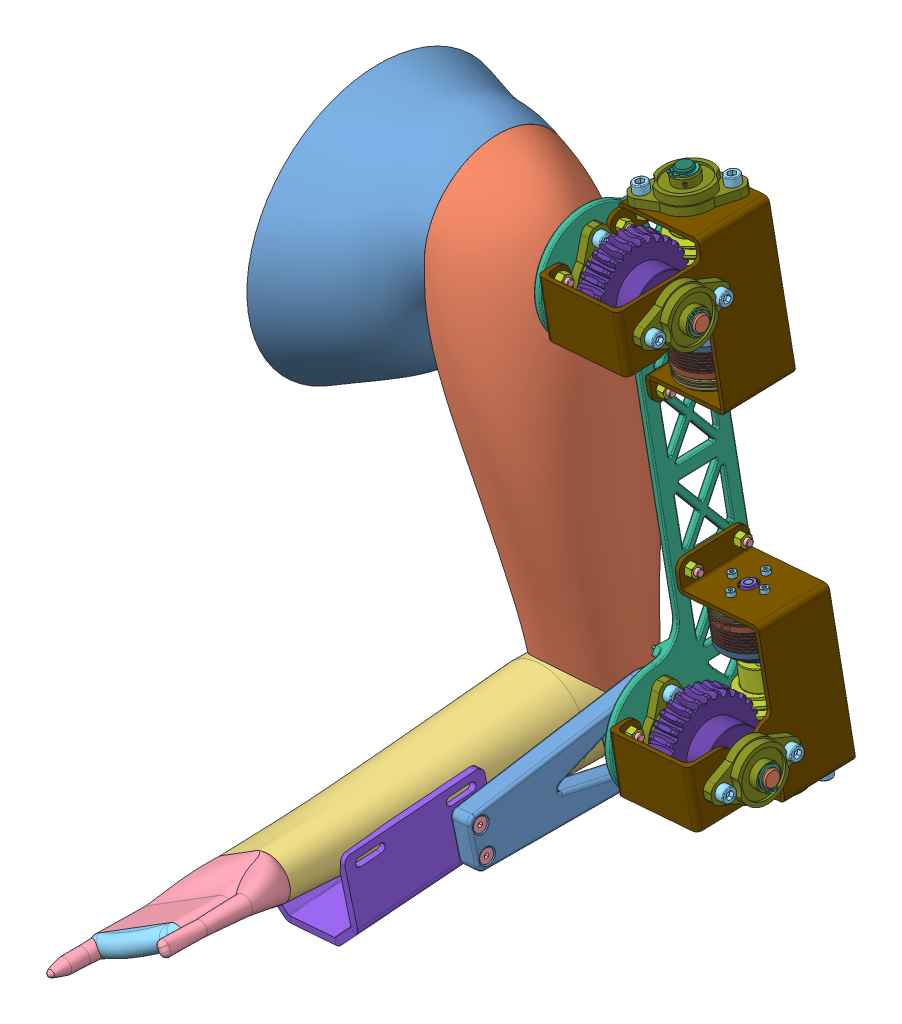
SolidWorks assembly Arm-Hand Assembly, configuration Default. Lengths in mm.
Overall size (296.71 409.91 340.99).
128 component instances, 26 part files, 116 mates.
Components (placement in the parent):
- Shoulder-1: Shoulder [Default] at (17.6912 210.9448 148.974) size (87.07 197.56 194.22)
- Shoulder-Elbow-1: Shoulder-Elbow [Default] at (104.7512 155.844 148.7388) x (1 0 0) z (0 -0.025169 0.999683) size (100.42 353.15 118.43)
- Elbow-Wrist-1: Elbow-Wrist [Πιο λεπτός αγκώνας] at (171.3594 -110.0701 142.044) x (-0.844554 -0.535174 -0.017826) z (-0.535135 0.844735 -0.00729) size (67.58 250.01 67.58)
- Wrist-Palm-1: Wrist-Palm [Default] at (166.6196 -110.9157 391.9976) x (0.844554 0.535174 0.017826) z (-0.018959 -0.003382 0.999815) size (95.76 31.54 113.53) (hidden)
- (Before Fingers)-1: (Before Fingers) [Default] at (160.2039 -114.3338 466.8783) x (-0.844554 -0.535174 -0.017826) z (-0.535135 0.844735 -0.00729) size (79 12.74 14.13) (hidden)
- upper-arm_linkage-1: upper-arm_linkage [Default] at (209.4073 37.5981 149.2159) x (0.035763 0.066972 -0.997114) z (0.992121 0.117497 0.043476) size (112.68 362.92 15.08)
- SW1_5-R1 (10)_On-1: SW1_5-R1 (10)_On [Default] at (261.9713 -113.4103 105.3558) x (-0.120069 0.990812 0.062242) z (0.544525 0.013304 0.838639) size (50 35.25 35.51)
  - SWG2-R1P_On-1: SWG2-R1P_On [Default] at (-1.7952 0 0) size (50 35.25 35.51)
- KDE4014XF-380KV-1: KDE4014XF-380KV [Default] at (253.9021 -46.8229 109.5388) x (-0.645085 -0.125522 0.753731) z (-0.120069 0.990812 0.062242) size (65.05 65.05 41.75)
  - KDE4014XF-380KV.STEP-1: KDE4014XF-380KV.STEP [Default] at origin size (65.05 65.05 41.75)
    - KDE-D5-SECURITY-RING-ASSEMBLY.STEP-1: KDE-D5-SECURITY-RING-ASSEMBLY.STEP [Default] at (0 0 23) x (-0.587785 0.809017 0) z (0 0 1) size (9.5 9.5 4.75)
      - KDE-D5-SECURITY_RING.STEP-1: KDE-D5-SECURITY_RING.STEP [Default] at origin size (9.5 9.5 4.75)
      - M3 x 3MM SOCKET HEAD SET SCREW KNURLED CUP POINT.STEP-1: M3 x 3MM SOCKET HEAD SET SCREW KNURLED CUP POINT.STEP [Default] at (0 3.375 2) x (-1 0 0) z (0 1 0) size (3 3 3.01)
      - M3 x 3MM SOCKET HEAD SET SCREW KNURLED CUP POINT.STEP-2: M3 x 3MM SOCKET HEAD SET SCREW KNURLED CUP POINT.STEP [Default] at (-3.375 0 2) x (0 0 -1) z (-1 0 0) size (3 3 3.01)
    - DT3914-24P-FRONT-COVER-D5-V2.STEP-1: DT3914-24P-FRONT-COVER-D5-V2.STEP [Default] at origin size (46.5 46.5 11)
    - DT3914-HOUSING.STEP-1: DT3914-HOUSING.STEP [Default] at origin size (46.5 46.5 17)
    - DT3914-REAR-COVER.STEP-1: DT3914-REAR-COVER.STEP [Default] x (-0.707107 -0.707107 0) z (0 0 -1) size (46 46 25)
    - RADIAL BALL BEARING 625ZZ.STEP-1: RADIAL BALL BEARING 625ZZ.STEP [Default] at (0 0 20) size (16 16 5)
    - DT3914-SHAFT-D5-V2.STEP-1: DT3914-SHAFT-D5-V2.STEP [Default] at (0 0 -11.75) x (-0.809017 -0.587785 0) z (0 0 1) size (6 6 41.75)
- Shaft_Motor_Gear-1: Shaft_Motor_Gear [Default] at (254.9827 -55.7403 108.9786) x (0.645085 0.125522 -0.753731) z (0.120069 -0.990812 -0.062242) size (30 30 95)
- UFL001J-1: UFL001J [Default] at (233.8767 -126.4215 149.106) x (-0.120069 0.990812 0.062242) z (0.992121 0.117497 0.043476) size (63 38 16)
  - UFL001 -Housing-1: UFL001 -Housing [Default] at (24 0 0) size (63 38 16)
- UFL001J-2: UFL001J [Default] at (293.3645 -93.7475 129.3647) x (-0.035752 -0.067069 0.997108) z (0.992121 0.117497 0.043476) size (63 38 16)
  - UFL001 -Housing-1: UFL001 -Housing [Default] at (24 0 0) size (63 38 16)
- UFL001 -Housing-1: UFL001 -Housing [Default] at (263.9879 -130.0512 104.3105) x (0.726824 0.130439 -0.674324) z (0.120069 -0.990812 -0.062242) size (63 38 16)
- AG2-30R1_On-1: AG2-30R1_On [Default] at (249.3492 -100.4683 151.4041) x (0.113097 -0.989255 0.09265) z (0.992121 0.117497 0.043476) size (65.95 66.01 33.01)
  - AG2-30R1-1_On-1: AG2-30R1-1_On [Default] x (1 0 0) z (0 0 -1) size (65.95 66.01 33.01)
- Motor-Bracket-1: Motor-Bracket [3D print] at (251.1405 -24.0343 110.9704) x (0.992121 0.117497 0.043476) z (0.035763 0.066972 -0.997114) size (62 127 110)
- forearm_connector-1: forearm_connector [Default] at (216.6092 -104.3457 149.9694) x (0.030334 0.11141 -0.993311) z (0.992121 0.117497 0.043476) size (160 55 17.5)
- Elbow_axle-1: Elbow_axle [Default] at (209.1683 -105.2269 149.6433) x (0.992121 0.117497 0.043476) z (-0.030334 -0.11141 0.993311) size (103 40 40)
- parallel_din-1: parallel_din [Parallel key A5 x 5 x 28 DIN 6885] at (251.2924 -91.7279 152.4437) x (-0.992121 -0.117497 -0.043476) z (-0.030334 -0.11141 0.993311) size (28 5 5)
- parallel_din-2: parallel_din [Parallel key A5 x 5 x 28 DIN 6885] at (268.1809 -111.2932 111.0229) x (0.120069 -0.990812 -0.062242) z (0.645085 0.125522 -0.753731) size (28 5 5)
- socket countersunk head screw_din-1: socket countersunk head screw_din [DIN 7991 - M5 x 16 --- 10.8N] at (223.2394 -104.9082 162.6929) x (-0.992121 -0.117497 -0.043476) z (-0.048298 0.678907 -0.732634) size (16 9.64 9.64)
- socket countersunk head screw_din-5: socket countersunk head screw_din [DIN 7991 - M5 x 16 --- 10.8N] at (222.0991 -91.1805 151.6136) x (-0.992121 -0.117497 -0.043476) z (-0.048298 0.678907 -0.732634) size (16 9.64 9.64)
- socket countersunk head screw_din-3: socket countersunk head screw_din [DIN 7991 - M5 x 16 --- 10.8N] at (225.138 -115.8506 148.9394) x (-0.992121 -0.117497 -0.043476) z (-0.048298 0.678907 -0.732634) size (16 9.64 9.64)
- socket countersunk head screw_din-4: socket countersunk head screw_din [DIN 7991 - M5 x 16 --- 10.8N] at (223.9977 -102.1229 137.8601) x (-0.992121 -0.117497 -0.043476) z (-0.048298 0.678907 -0.732634) size (16 9.64 9.64)
- socket head cap screw_din-1: socket head cap screw_din [DIN 912 M3 x 10 --- 10N] at (248.3971 -64.1702 101.9384) x (-0.120069 0.990812 0.062242) z (0.598617 0.022241 0.800726) size (13 5.5 5.5)
- socket head cap screw_din-2: socket head cap screw_din [DIN 912 M3 x 10 --- 10N] at (249.4924 -64.922 116.018) x (-0.120069 0.990812 0.062242) z (0.791985 0.133402 -0.595788) size (13 5.5 5.5)
- socket head cap screw_din-3: socket head cap screw_din [DIN 912 M3 x 10 --- 10N] at (263.4895 -63.1633 115.023) x (-0.120069 0.990812 0.062242) z (-0.598617 -0.022241 -0.800726) size (13 5.5 5.5)
- socket head cap screw_din-4: socket head cap screw_din [DIN 912 M3 x 10 --- 10N] at (262.3941 -62.4115 100.9434) x (-0.120069 0.990812 0.062242) z (-0.791985 -0.133402 0.595788) size (13 5.5 5.5)
- socket head cap screw_din-7: socket head cap screw_din [DIN 912 M6 x 16 --- 16N] at (303.5539 -95.5569 177.7476) x (-0.992121 -0.117497 -0.043476) z (-0.043476 0.648354 -0.760097) size (22 10 10)
- socket head cap screw_din-8: socket head cap screw_din [DIN 912 M6 x 16 --- 16N] at (305.27 -92.3375 129.8864) x (-0.992121 -0.117497 -0.043476) z (-0.043476 0.648354 -0.760097) size (22 10 10)
- socket head cap screw_din-9: socket head cap screw_din [DIN 912 M6 x 16 --- 16N] at (282.8725 -138.8104 87.3798) x (-0.120069 0.990812 0.062242) z (0.743313 0.131282 -0.655935) size (22 10 10)
- socket head cap screw_din-10: socket head cap screw_din [DIN 912 M6 x 16 --- 16N] at (247.985 -145.0715 119.7473) x (-0.120069 0.990812 0.062242) z (0.743313 0.131282 -0.655935) size (22 10 10)
- socket head cap screw_din-11: socket head cap screw_din [DIN 912 M6 x 10 --- 10N] at (245.7821 -125.0115 149.6277) x (-0.992121 -0.117497 -0.043476) z (-0.043476 0.648354 -0.760097) size (16 10 10)
- socket head cap screw_din-12: socket head cap screw_din [DIN 912 M6 x 10 --- 10N] at (240.0188 -77.4525 152.6153) x (-0.992121 -0.117497 -0.043476) z (-0.000111 0.347848 -0.937551) size (16 10 10)
- STWN12-1: STWN12 [Default] at (308.8021 -93.4273 154.0094) x (0.992121 0.117497 0.043476) z (-0.032447 -0.094204 0.995024) size (1 16.8 14.65)
- STWN12-2: STWN12 [Default] at (266.0201 -146.8207 103.257) x (0.120069 -0.990812 -0.062242) z (0.985877 0.126374 -0.109888) size (1 16.8 14.65)
- hex nut gradec_din-1: hex nut gradec_din [Hexagon Nut ISO 4034 - M6 - N] at (288.6721 -97.3193 177.0954) x (-0.056706 0.111714 0.992121) z (0.992121 0.117497 0.043476) size (10 11.55 6.1)
- hex nut gradec_din-2: hex nut gradec_din [Hexagon Nut ISO 4034 - M6 - N] at (290.3882 -94.1 129.2343) x (-0.056706 0.111714 0.992121) z (0.992121 0.117497 0.043476) size (10 11.55 6.1)
- hex nut gradec_din-3: hex nut gradec_din [Hexagon Nut ISO 4034 - M6 - N] at (246.1839 -130.2093 120.681) x (-0.991129 -0.116037 -0.064796) z (0.120069 -0.990812 -0.062242) size (10 11.55 6.1)
- hex nut gradec_din-4: hex nut gradec_din [Hexagon Nut ISO 4034 - M6 - N] at (281.0715 -123.9482 88.3134) x (-0.984636 -0.126859 0.119992) z (0.120069 -0.990812 -0.062242) size (10 11.55 6.1)
- socket head cap screw_din-13: socket head cap screw_din [DIN 912 M3 x 8 --- 8N] at (262.8216 -16.6207 111.8873) x (0.120069 -0.990812 -0.062242) z (0.031773 0.066499 -0.99728) size (11 5.5 5.5)
- socket head cap screw_din-14: socket head cap screw_din [DIN 912 M3 x 8 --- 8N] at (249.973 -18.9265 123.8078) x (0.120069 -0.990812 -0.062242) z (0.992257 0.117765 0.039465) size (11 5.5 5.5)
- socket head cap screw_din-15: socket head cap screw_din [DIN 912 M3 x 8 --- 8N] at (238.0186 -19.5581 110.8004) x (0.120069 -0.990812 -0.062242) z (-0.031773 -0.066499 0.99728) size (11 5.5 5.5)
- socket head cap screw_din-16: socket head cap screw_din [DIN 912 M3 x 8 --- 8N] at (250.8671 -17.2522 98.8799) x (0.120069 -0.990812 -0.062242) z (-0.992257 -0.117765 -0.039465) size (11 5.5 5.5)
- Armguard_SheetMetal-1: Armguard_SheetMetal [Default] at (199.8126 -143.4556 351.4502) x (0.030334 0.11141 -0.993311) z (0.992121 0.117497 0.043476) size (100 63.56 75.97)
- socket countersunk head screw_din-7: socket countersunk head screw_din [DIN 7991 - M5 x 20 --- 14.8N] at (218.6113 -107.5738 275.5102) x (-0.992121 -0.117497 -0.043476) z (0.059925 -0.749813 0.65893) size (20 9.64 9.64)
- socket countersunk head screw_din-9: socket countersunk head screw_din [DIN 7991 - M5 x 20 --- 14.8N] at (221.0424 -127.3099 273.3708) x (-0.992121 -0.117497 -0.043476) z (0.059925 -0.749813 0.65893) size (20 9.64 9.64)
- Motor-Bracket-2: Motor-Bracket [Mirror] at (239.504 71.9904 117.0026) x (0.992121 0.117497 0.043476) z (0.035763 0.066972 -0.997114) size (62 127 110)
- KDE4014XF-380KV-2: KDE4014XF-380KV [Default] at (231.9396 134.4115 120.9239) x (0.946199 0.133189 -0.294904) z (0.120069 -0.990812 -0.062242) size (65.05 65.05 41.75)
  - KDE4014XF-380KV.STEP-1: KDE4014XF-380KV.STEP [Default] at origin size (65.05 65.05 41.75)
    - KDE-D5-SECURITY-RING-ASSEMBLY.STEP-1: KDE-D5-SECURITY-RING-ASSEMBLY.STEP [Default] at (0 0 23) x (-0.587785 0.809017 0) z (0 0 1) size (9.5 9.5 4.75)
      - KDE-D5-SECURITY_RING.STEP-1: KDE-D5-SECURITY_RING.STEP [Default] at origin size (9.5 9.5 4.75)
      - M3 x 3MM SOCKET HEAD SET SCREW KNURLED CUP POINT.STEP-1: M3 x 3MM SOCKET HEAD SET SCREW KNURLED CUP POINT.STEP [Default] at (0 3.375 2) x (-1 0 0) z (0 1 0) size (3 3 3.01)
      - M3 x 3MM SOCKET HEAD SET SCREW KNURLED CUP POINT.STEP-2: M3 x 3MM SOCKET HEAD SET SCREW KNURLED CUP POINT.STEP [Default] at (-3.375 0 2) x (0 0 -1) z (-1 0 0) size (3 3 3.01)
    - DT3914-24P-FRONT-COVER-D5-V2.STEP-1: DT3914-24P-FRONT-COVER-D5-V2.STEP [Default] at origin size (46.5 46.5 11)
    - DT3914-HOUSING.STEP-1: DT3914-HOUSING.STEP [Default] at origin size (46.5 46.5 17)
    - DT3914-REAR-COVER.STEP-1: DT3914-REAR-COVER.STEP [Default] x (-0.707107 -0.707107 0) z (0 0 -1) size (46 46 25)
    - RADIAL BALL BEARING 625ZZ.STEP-1: RADIAL BALL BEARING 625ZZ.STEP [Default] at (0 0 20) size (16 16 5)
    - DT3914-SHAFT-D5-V2.STEP-1: DT3914-SHAFT-D5-V2.STEP [Default] at (0 0 -11.75) x (-0.809017 -0.587785 0) z (0 0 1) size (6 6 41.75)
- Shaft_Motor_Gear-2: Shaft_Motor_Gear [Default] at (230.859 143.3289 121.4841) x (-0.946199 -0.133189 0.294904) z (-0.120069 0.990812 0.062242) size (30 30 95)
- UFL001J-3: UFL001J [Default] at (194.144 201.4533 169.7029) x (0.120069 -0.990812 -0.062242) z (0.992121 0.117497 0.043476) size (63 38 16)
  - UFL001 -Housing-1: UFL001 -Housing [Default] at (24 0 0) size (63 38 16)
- UFL001J-4: UFL001J [Default] at (259.3957 186.5636 146.9738) x (-0.035775 -0.066875 0.99712) z (0.992121 0.117497 0.043476) size (63 38 16)
  - UFL001 -Housing-1: UFL001 -Housing [Default] at (24 0 0) size (63 38 16)
- AG2-30R1_On-2: AG2-30R1_On [Default] at (215.3799 179.8475 169.0134) x (0.11957 -0.78445 -0.608557) z (0.992121 0.117497 0.043476) size (65.95 66.01 33.01)
  - AG2-30R1-1_On-1: AG2-30R1-1_On [Default] x (1 0 0) z (0 0 -1) size (65.95 66.01 33.01)
- SW1_5-R1 (10)_On-2: SW1_5-R1 (10)_On [Default] at (223.8704 200.9989 125.1069) x (0.120069 -0.990812 -0.062242) z (-0.024383 0.059734 -0.997916) size (50 35.25 35.51)
  - SWG2-R1P_On-1: SWG2-R1P_On [Default] at (-1.7952 0 0) size (50 35.25 35.51)
- Elbow_axle-2: Elbow_axle [Default] at (175.199 175.0888 167.2526) x (0.992121 0.117497 0.043476) z (-0.01288 0.440846 -0.897491) size (103 40 40)
- parallel_din-3: parallel_din [Parallel key A5 x 5 x 28 DIN 6885] at (219.4155 172.6361 165.4133) x (-0.992121 -0.117497 -0.043476) z (-0.01288 0.440846 -0.897491) size (28 5 5)
- parallel_din-4: parallel_din [Parallel key A5 x 5 x 28 DIN 6885] at (226.6292 199.1101 133.1055) x (-0.120069 0.990812 0.062242) z (-0.946199 -0.133189 0.294904) size (28 5 5)
- socket head cap screw_din-17: socket head cap screw_din [DIN 912 M3 x 10 --- 10N] at (226.8936 151.4902 112.4471) x (0.120069 -0.990812 -0.062242) z (-0.090448 0.051518 -0.994568) size (13 5.5 5.5)
- socket head cap screw_din-18: socket head cap screw_din [DIN 912 M6 x 16 --- 16N] at (269.584 184.7635 195.3572) x (-0.992121 -0.117497 -0.043476) z (-0.100681 0.541229 0.834826) size (22 10 10)
- socket head cap screw_din-19: socket head cap screw_din [DIN 912 M6 x 16 --- 16N] at (271.3012 187.9735 147.4955) x (-0.992121 -0.117497 -0.043476) z (-0.100681 0.541229 0.834826) size (22 10 10)
- socket head cap screw_din-20: socket head cap screw_din [DIN 912 M6 x 16 --- 16N] at (237.8568 232.6601 110.7154) x (0.120069 -0.990812 -0.062242) z (-0.743313 -0.131282 0.655935) size (22 10 10)
- socket head cap screw_din-21: socket head cap screw_din [DIN 912 M6 x 16 --- 16N] at (202.9692 226.399 143.083) x (0.120069 -0.990812 -0.062242) z (-0.743313 -0.131282 0.655935) size (22 10 10)
- socket head cap screw_din-22: socket head cap screw_din [DIN 912 M6 x 10 --- 10N] at (206.0494 202.8632 170.2247) x (-0.992121 -0.117497 -0.043476) z (-0.100681 0.541229 0.834826) size (16 10 10)
- socket head cap screw_din-23: socket head cap screw_din [DIN 912 M6 x 10 --- 10N] at (211.8127 155.3042 167.237) x (-0.992121 -0.117497 -0.043476) z (-0.068643 0.21951 0.973192) size (16 10 10)
- STWN12-3: STWN12 [Default] at (274.8327 186.8884 171.6187) x (0.992121 0.117497 0.043476) z (-0.015049 0.45628 -0.889709) size (1 16.8 14.65)
- STWN12-4: STWN12 [Default] at (219.8217 234.4093 127.2057) x (-0.120069 0.990812 0.062242) z (-0.898996 -0.081916 -0.430229) size (1 16.8 14.65)
- hex nut gradec_din-5: hex nut gradec_din [Hexagon Nut ISO 4034 - M6 - N] at (248.6502 182.2843 194.4399) x (-0.013662 -0.243489 0.969807) z (-0.992121 -0.117497 -0.043476) size (10 11.55 6.1)
- hex nut gradec_din-6: hex nut gradec_din [Hexagon Nut ISO 4034 - M6 - N] at (250.3674 185.4943 146.5781) x (-0.013662 -0.243489 0.969807) z (-0.992121 -0.117497 -0.043476) size (10 11.55 6.1)
- hex nut gradec_din-7: hex nut gradec_din [Hexagon Nut ISO 4034 - M6 - N] at (205.5027 205.4929 141.7696) x (-0.991129 -0.116037 -0.064796) z (0.120069 -0.990812 -0.062242) size (10 11.55 6.1)
- hex nut gradec_din-8: hex nut gradec_din [Hexagon Nut ISO 4034 - M6 - N] at (240.3902 211.7539 109.4021) x (-0.984636 -0.126859 0.119992) z (0.120069 -0.990812 -0.062242) size (10 11.55 6.1)
- socket head cap screw_din-24: socket head cap screw_din [DIN 912 M3 x 8 --- 8N] at (247.8232 107.1467 119.6623) x (-0.120069 0.990812 0.062242) z (-0.031773 -0.066499 0.99728) size (11 5.5 5.5)
- UFL001 -Housing-3: UFL001 -Housing [Default] at (221.8538 217.6398 126.1523) x (-0.726824 -0.130439 0.674324) z (-0.120069 0.990812 0.062242) size (63 38 16)
- socket head cap screw_din-25: socket head cap screw_din [DIN 912 M3 x 8 --- 8N] at (234.9746 104.8408 131.5828) x (-0.120069 0.990812 0.062242) z (-0.992257 -0.117765 -0.039465) size (11 5.5 5.5)
- socket head cap screw_din-26: socket head cap screw_din [DIN 912 M3 x 8 --- 8N] at (223.0201 104.2093 118.5754) x (-0.120069 0.990812 0.062242) z (0.031773 0.066499 -0.99728) size (11 5.5 5.5)
- socket head cap screw_din-27: socket head cap screw_din [DIN 912 M3 x 8 --- 8N] at (235.8687 106.5151 106.655) x (-0.120069 0.990812 0.062242) z (0.992257 0.117765 0.039465) size (11 5.5 5.5)
- socket countersunk head screw_din-10: socket countersunk head screw_din [DIN 7991 - M5 x 16 --- 10.8N] at (231.3005 -120.2615 86.2449) x (0.992121 0.117497 0.043476) z (-0.04206 -0.014506 0.99901) size (16 9.64 9.64)
- hex nut gradec_din-9: hex nut gradec_din [Hexagon Nut ISO 4034 - M5 - N] at (244.3618 -118.7147 86.8173) x (0.056706 -0.111714 -0.992121) z (0.992121 0.117497 0.043476) size (8 9.24 5.6)
- hex nut gradec_din-10: hex nut gradec_din [Hexagon Nut ISO 4034 - M5 - N] at (237.061 -91.0569 178.6736) x (0.056706 -0.111714 -0.992121) z (0.992121 0.117497 0.043476) size (8 9.24 5.6)
- hex nut gradec_din-11: hex nut gradec_din [Hexagon Nut ISO 4034 - M5 - N] at (240.0628 -115.8272 177.1176) x (0.056706 -0.111714 -0.992121) z (0.992121 0.117497 0.043476) size (8 9.24 5.6)
- hex nut gradec_din-12: hex nut gradec_din [Hexagon Nut ISO 4034 - M5 - N] at (242.7525 -121.7285 131.6874) x (0.056706 -0.111714 -0.992121) z (0.992121 0.117497 0.043476) size (8 9.24 5.6)
- hex nut gradec_din-13: hex nut gradec_din [Hexagon Nut ISO 4034 - M5 - N] at (231.5144 -12.6978 93.4772) x (0.056706 -0.111714 -0.992121) z (0.992121 0.117497 0.043476) size (8 9.24 5.6)
- hex nut gradec_din-14: hex nut gradec_din [Hexagon Nut ISO 4034 - M5 - N] at (230.2627 -15.0418 128.3762) x (0.056706 -0.111714 -0.992121) z (0.992121 0.117497 0.043476) size (8 9.24 5.6)
- socket countersunk head screw_din-11: socket countersunk head screw_din [DIN 7991 - M5 x 16 --- 10.8N] at (223.9998 -92.6038 178.1013) x (0.992121 0.117497 0.043476) z (-0.04206 -0.014506 0.99901) size (16 9.64 9.64)
- socket countersunk head screw_din-12: socket countersunk head screw_din [DIN 7991 - M5 x 16 --- 10.8N] at (227.0015 -117.3741 176.5452) x (0.992121 0.117497 0.043476) z (-0.04206 -0.014506 0.99901) size (16 9.64 9.64)
- socket countersunk head screw_din-13: socket countersunk head screw_din [DIN 7991 - M5 x 16 --- 10.8N] at (229.6912 -123.2753 131.1151) x (0.992121 0.117497 0.043476) z (-0.04206 -0.014506 0.99901) size (16 9.64 9.64)
- socket countersunk head screw_din-14: socket countersunk head screw_din [DIN 7991 - M5 x 16 --- 10.8N] at (218.4531 -14.2446 92.9049) x (0.992121 0.117497 0.043476) z (-0.04206 -0.014506 0.99901) size (16 9.64 9.64)
- socket countersunk head screw_din-15: socket countersunk head screw_din [DIN 7991 - M5 x 16 --- 10.8N] at (217.2014 -16.5886 127.8039) x (0.992121 0.117497 0.043476) z (-0.04206 -0.014506 0.99901) size (16 9.64 9.64)
- hex nut gradec_din-15: hex nut gradec_din [Hexagon Nut ISO 4034 - M5 - N] at (199.6736 203.548 106.8596) x (0.013662 0.243489 -0.969807) z (-0.992121 -0.117497 -0.043476) size (8 9.24 5.6)
- socket countersunk head screw_din-16: socket countersunk head screw_din [DIN 7991 - M5 x 16 --- 10.8N] at (192.1682 202.6591 106.5307) x (0.992121 0.117497 0.043476) z (0.029367 0.119251 -0.99243) size (16 9.64 9.64)
- hex nut gradec_din-16: hex nut gradec_din [Hexagon Nut ISO 4034 - M5 - N] at (200.537 163.8352 194.4837) x (0.013662 0.243489 -0.969807) z (-0.992121 -0.117497 -0.043476) size (8 9.24 5.6)
- hex nut gradec_din-17: hex nut gradec_din [Hexagon Nut ISO 4034 - M5 - N] at (197.5352 188.6055 196.0398) x (0.013662 0.243489 -0.969807) z (-0.992121 -0.117497 -0.043476) size (8 9.24 5.6)
- hex nut gradec_din-18: hex nut gradec_din [Hexagon Nut ISO 4034 - M5 - N] at (198.0642 200.5342 151.7297) x (0.013662 0.243489 -0.969807) z (-0.992121 -0.117497 -0.043476) size (8 9.24 5.6)
- hex nut gradec_din-19: hex nut gradec_din [Hexagon Nut ISO 4034 - M5 - N] at (212.521 97.531 100.1997) x (0.013662 0.243489 -0.969807) z (-0.992121 -0.117497 -0.043476) size (8 9.24 5.6)
- hex nut gradec_din-20: hex nut gradec_din [Hexagon Nut ISO 4034 - M5 - N] at (211.2693 95.187 135.0986) x (0.013662 0.243489 -0.969807) z (-0.992121 -0.117497 -0.043476) size (8 9.24 5.6)
- socket countersunk head screw_din-17: socket countersunk head screw_din [DIN 7991 - M5 x 16 --- 10.8N] at (193.0316 162.9463 194.1548) x (0.992121 0.117497 0.043476) z (0.029367 0.119251 -0.99243) size (16 9.64 9.64)
- socket countersunk head screw_din-18: socket countersunk head screw_din [DIN 7991 - M5 x 16 --- 10.8N] at (190.0298 187.7166 195.7109) x (0.992121 0.117497 0.043476) z (0.029367 0.119251 -0.99243) size (16 9.64 9.64)
- socket countersunk head screw_din-19: socket countersunk head screw_din [DIN 7991 - M5 x 16 --- 10.8N] at (190.5588 199.6454 151.4008) x (0.992121 0.117497 0.043476) z (0.029367 0.119251 -0.99243) size (16 9.64 9.64)
- socket countersunk head screw_din-20: socket countersunk head screw_din [DIN 7991 - M5 x 16 --- 10.8N] at (205.0156 96.6422 99.8708) x (0.992121 0.117497 0.043476) z (0.029367 0.119251 -0.99243) size (16 9.64 9.64)
- socket countersunk head screw_din-21: socket countersunk head screw_din [DIN 7991 - M5 x 16 --- 10.8N] at (203.7639 94.2982 134.7697) x (0.992121 0.117497 0.043476) z (0.029367 0.119251 -0.99243) size (16 9.64 9.64)
- socket head cap screw_din-28: socket head cap screw_din [DIN 912 M3 x 10 --- 10N] at (220.4365 149.9235 124.9311) x (0.120069 -0.990812 -0.062242) z (-0.988637 -0.125047 0.083431) size (13 5.5 5.5)
- socket head cap screw_din-29: socket head cap screw_din [DIN 912 M3 x 10 --- 10N] at (232.9033 151.0205 131.517) x (0.120069 -0.990812 -0.062242) z (0.090448 -0.051518 0.994568) size (13 5.5 5.5)
- socket head cap screw_din-30: socket head cap screw_din [DIN 912 M3 x 10 --- 10N] at (239.3605 152.5872 119.033) x (0.120069 -0.990812 -0.062242) z (0.988637 0.125047 -0.083431) size (13 5.5 5.5)
Mates (geometry in assembly coordinates):
- Coincident1: coincident aligned: circle of Ώμος-1; circle of Ώμος-Αγκώνας-1
- Concentric1: concentric: sphere of Shoulder-Elbow-1; sphere of Elbow-Wrist-1
- Coincident6: coincident aligned: line of Elbow-Wrist-1 through (162.232 -132.2745 391.8421) axis (0.844554 0.535174 0.017826); line of Wrist-Palm-1 through (162.232 -132.2745 391.8421) axis (0.844554 0.535174 0.017826)
- Coincident7: coincident aligned: circle of Αγκώνας-Καρπός-1; circle of Καρπός-Παλάμη-1
- Coincident8: coincident anti-aligned: plane of Wrist-Palm-1 through (187.6519 -96.9407 467.4576) normal (-0.018959 -0.003382 0.999815); plane of (Before Fingers)-1 through (187.6519 -96.9407 467.4576) normal (0.018959 0.003382 -0.999815)
- Coincident9: coincident anti-aligned: plane of Wrist-Palm-1 through (187.6519 -96.9407 467.4576) normal (-0.018959 -0.003382 0.999815); plane of (Before Fingers)-1 through (187.6519 -96.9407 467.4576) normal (0.018959 0.003382 -0.999815)
- Concentric2: concentric aligned: circle of Καρπός-Παλάμη-1; circle of Πριν τα δάχτυλα-1
- Concentric3: concentric aligned: circle of Καρπός-Παλάμη-1; circle of Πριν τα δάχτυλα-1
- Coincident10: coincident anti-aligned: circle of Καρπός-Παλάμη-1; circle of Πριν τα δάχτυλα-1
- Lock4: lock: unknown of Wrist-Palm-1; unknown of Finger-3
- Lock5: lock: unknown of Wrist-Palm-1; unknown of Finger-1
- Lock6: lock: unknown of Wrist-Palm-1; unknown of Finger-2
- InPlace1: in place: plane of ? through (171.3594 -109.5771 131.2229) normal (-0.54967 0.83443 0.039862); plane of ? through (171.3594 -109.5771 131.2229) normal (-0.54967 0.83443 0.039862); moOrthogonalPlaneRef_w of ? through (171.3594 -109.5771 131.2229) normal (-0.54967 0.83443 0.039862); plane of ? through (171.3594 -109.5771 131.2229) normal (0.119038 0.031006 0.992406); plane of ? through (171.3594 -109.5771 131.2229) normal (-0.54967 0.83443 0.039862); plane of ? through (171.3594 -109.5771 131.2229) normal (-0.826857 -0.55024 0.116372); plane of Elbow-Wrist-1 through (171.3594 -110.0701 142.044) normal (-0.535135 0.844735 -0.00729); unknown of ?
- Coincident11: coincident aligned: plane of ?; plane of ?
- Coincident12: coincident aligned: moOrthogonalPlaneRef_w of Elbow-Wrist-1; plane of Part9-1 through (171.3594 -109.5771 131.2229) normal (0.119038 0.031006 0.992406)
- Coincident13: coincident anti-aligned: moOrthogonalPlaneRef_w of Elbow-Wrist-1; plane of Part9-1 through (171.3594 -109.5771 131.2229) normal (-0.826857 -0.55024 0.116372)
- Parallel1: parallel aligned: plane of Part2-1 through (110.6624 84.3937 167.2574) normal (0 0 1)
- Parallel12: parallel aligned: plane of SW1_5-R1 (10)_On-1 through (261.9713 -113.4103 105.3558) normal (-0.120069 0.990812 0.062242); plane of KDE4014XF-380KV-1 through (253.9021 -46.8229 109.5388) normal (-0.120069 0.990812 0.062242)
- Concentric16: concentric aligned: cylinder of SW1_5-R1 (10)_On-1/SWG2-R1P_On-1 through (256.1834 -65.6484 108.3562) axis (-0.120069 0.990812 0.062242) radius 6; cylinder of Shaft_Motor_Gear-1 through (266.3893 -149.8674 103.0656) axis (-0.120069 0.990812 0.062242) radius 6
- Distance3: distance = 5 mm anti-aligned: plane of Shaft_Motor_Gear-1 through (255.5831 -60.6943 108.6674) normal (0.120069 -0.990812 -0.062242); plane of SW1_5-R1 (10)_On-1/SWG2-R1P_On-1 through (272.9512 -63.8296 111.749) normal (-0.120069 0.990812 0.062242)
- Concentric17: concentric anti-aligned: cylinder of KDE4014XF-380KV-1/KDE4014XF-380KV.STEP-1/DT3914-24P-FRONT-COVER-D5-V2.STEP-1 through (262.5289 -55.2368 115.5209) axis (0.120069 -0.990812 -0.062242) radius 1.25; cylinder of Shaft_Motor_Gear-1 through (263.1293 -60.1908 115.2097) axis (-0.120069 0.990812 0.062242) radius 1.5
- Concentric13: concentric anti-aligned: cylinder of Shaft_Motor_Gear-1 through (248.0369 -61.1978 102.1251) axis (-0.120069 0.990812 0.062242) radius 1.5; cylinder of KDE4014XF-380KV-1/KDE4014XF-380KV.STEP-1/DT3914-24P-FRONT-COVER-D5-V2.STEP-1 through (247.4365 -56.2437 102.4364) axis (0.120069 -0.990812 -0.062242) radius 1.25
- Coincident16: coincident anti-aligned: plane of KDE4014XF-380KV-1/KDE4014XF-380KV.STEP-1/DT3914-24P-FRONT-COVER-D5-V2.STEP-1 through (254.9827 -55.7403 108.9786) normal (0.120069 -0.990812 -0.062242); plane of Shaft_Motor_Gear-1 through (254.9827 -55.7403 108.9786) normal (-0.120069 0.990812 0.062242)
- Concentric22: concentric aligned: cylinder of Shaft_Motor_Gear-1 through (266.3893 -149.8674 103.0656) axis (-0.120069 0.990812 0.062242) radius 6; cylinder of UFL001 -Housing-1 through (259.4253 -92.4003 106.6757) axis (-0.120069 0.990812 0.062242) radius 6
- Coincident53: coincident anti-aligned: plane of KDE4014XF-380KV-1/KDE4014XF-380KV.STEP-1/DT3914-REAR-COVER.STEP-1 through (251.1405 -24.0343 110.9704) normal (-0.120069 0.990812 0.062242); plane of Motor-Bracket-1 through (224.7513 -25.5911 84.847) normal (0.120069 -0.990812 -0.062242)
- Concentric25: concentric anti-aligned: cylinder of KDE4014XF-380KV-1/KDE4014XF-380KV.STEP-1/KDE-D5-SECURITY-RING-ASSEMBLY.STEP-1/KDE-D5-SECURITY_RING.STEP-1 through (251.1705 -24.282 110.9548) axis (-0.120069 0.990812 0.062242) radius 4.75; cylinder of Motor-Bracket-1 through (250.7803 -21.0618 111.1571) axis (0.120069 -0.990812 -0.062242) radius 6
- Concentric28: concentric anti-aligned: cylinder of forearm_connector-1 through (216.6092 -104.3457 149.9694) axis (-0.992121 -0.117497 -0.043476) radius 20; cylinder of Elbow_axle-1 through (311.3568 -93.1247 154.1213) axis (0.992121 0.117497 0.043476) radius 20
- Coincident54: coincident anti-aligned: plane of forearm_connector-1 through (216.6092 -104.3457 149.9694) normal (-0.992121 -0.117497 -0.043476); plane of Elbow_axle-1 through (214.1781 -84.6096 152.1088) normal (0.992121 0.117497 0.043476)
- Concentric29: concentric anti-aligned: cylinder of Elbow_axle-1 through (208.7892 -106.6195 162.0597) axis (-0.992121 -0.117497 -0.043476) radius 2.1; cylinder of forearm_connector-1 through (223.671 -104.8571 162.7118) axis (0.992121 0.117497 0.043476) radius 2.75
- Concentric30: concentric aligned: cylinder of Part31-1 through (226.0334 -103.2296 150.3824) axis (0.992121 0.117497 0.043476) radius 10; cylinder of Elbow_axle-1 through (311.3568 -93.1247 154.1213) axis (0.992121 0.117497 0.043476) radius 6
- Concentric35: concentric aligned: cylinder of AG2-30R1_On-1/AG2-30R1-1_On-1 through (282.0892 -96.5909 152.8388) axis (0.992121 0.117497 0.043476) radius 6; cylinder of Elbow_axle-1 through (311.3568 -93.1247 154.1213) axis (0.992121 0.117497 0.043476) radius 6
- GearMate2: gear = 300 : 10 mm: circle of SW1_5-R1 (10)_On-1/SWG2-R1P_On-1; cylinder of AG2-30R1_On-1/AG2-30R1-1_On-1 through (264.741 -71.827 136.7808) axis (-0.992121 -0.117497 -0.043476) radius 18
- Concentric36: concentric anti-aligned: cylinder of UFL001J-2/UFL001 -Housing-1 through (254.8059 -99.822 151.6432) axis (-0.992121 -0.117497 -0.043476) radius 6; cylinder of Elbow_axle-1 through (311.3568 -93.1247 154.1213) axis (0.992121 0.117497 0.043476) radius 6
- Coincident57: coincident anti-aligned: plane of Shaft_Motor_Gear-1 through (264.5279 -112.5357 107.6895) normal (0.754619 0.050348 0.654229); plane of parallel_din-2 through (261.6462 -88.7562 109.1833) normal (-0.754619 -0.050348 -0.654229)
- Slot1: slot aligned: cylinder of parallel_din-2 through (261.6462 -88.7562 109.1833) axis (0.754619 0.050348 0.654229) radius 2.5; cylinder of Shaft_Motor_Gear-1 through (264.5279 -112.5357 107.6895) axis (0.754619 0.050348 0.654229) radius 2.5; cylinder of parallel_din-2 through (264.4078 -111.5449 107.7517) axis (0.754619 0.050348 0.654229) radius 2.5; cylinder of Shaft_Motor_Gear-1 through (261.5261 -87.7654 109.2456) axis (0.754619 0.050348 0.654229) radius 2.5
- Parallel16: parallel aligned: plane of Shaft_Motor_Gear-1 through (262.9152 -112.8496 109.5738) normal (0.645085 0.125522 -0.753731); plane of parallel_din-2 through (263.2589 -88.4424 107.299) normal (0.645085 0.125522 -0.753731)
- Coincident58: coincident anti-aligned: plane of Elbow_axle-1 through (250.908 -96.7795 151.8654) normal (-0.121554 0.986804 0.106969); plane of parallel_din-1 through (274.7189 -93.9595 152.9089) normal (0.121554 -0.986804 -0.106969)
- Parallel17: parallel aligned: plane of Elbow_axle-1 through (250.9839 -96.5009 149.3822) normal (-0.030334 -0.11141 0.993311); plane of parallel_din-1 through (274.6431 -94.2381 155.3921) normal (-0.030334 -0.11141 0.993311)
- Slot2: slot aligned: cylinder of parallel_din-1 through (274.7189 -93.9595 152.9089) axis (-0.121554 0.986804 0.106969) radius 2.5; cylinder of Elbow_axle-1 through (275.7111 -93.842 152.9523) axis (-0.121554 0.986804 0.106969) radius 2.5; cylinder of parallel_din-1 through (251.9002 -96.662 151.9089) axis (-0.121554 0.986804 0.106969) radius 2.5; cylinder of Elbow_axle-1 through (250.908 -96.7795 151.8654) axis (-0.121554 0.986804 0.106969) radius 2.5
- Coincident60: coincident aligned: cone of forearm_connector-1 through (223.671 -104.8571 162.7118) axis (-0.992121 -0.117497 -0.043476); cone of socket countersunk head screw_din-1 through (222.7632 -104.9646 162.6721) axis (-0.992121 -0.117497 -0.043476)
- Concentric39: concentric anti-aligned: cylinder of UFL001 -Housing-1 through (282.1521 -132.8655 87.7532) axis (-0.120069 0.990812 0.062242) radius 3.5; cylinder of Motor-Bracket-1 through (281.0715 -123.9482 88.3134) axis (0.120069 -0.990812 -0.062242) radius 3.5
- Coincident61: coincident anti-aligned: plane of UFL001 -Housing-1 through (228.1793 -134.8422 111.5006) normal (-0.120069 0.990812 0.062242); plane of Motor-Bracket-1 through (263.9879 -130.0512 104.3105) normal (0.120069 -0.990812 -0.062242)
- Coincident62: coincident anti-aligned: plane of Shaft_Motor_Gear-1 through (255.5831 -60.6943 108.6674) normal (0.120069 -0.990812 -0.062242); plane of socket head cap screw_din-1 through (245.8589 -61.5647 103.7636) normal (-0.120069 0.990812 0.062242)
- Concentric40: concentric anti-aligned: cylinder of Shaft_Motor_Gear-1 through (248.0369 -61.1978 102.1251) axis (-0.120069 0.990812 0.062242) radius 1.5; cylinder of socket head cap screw_din-1 through (252.2093 -95.6285 99.9622) axis (0.120069 -0.990812 -0.062242) radius 1.5
- Coincident63: coincident anti-aligned: plane of UFL001J-2/UFL001 -Housing-1 through (291.3398 -74.324 123.0769) normal (-0.992121 -0.117497 -0.043476); plane of Motor-Bracket-1 through (285.3687 -19.9806 112.4703) normal (0.992121 0.117497 0.043476)
- Concentric42: concentric anti-aligned: cylinder of UFL001J-2/UFL001 -Housing-1 through (254.8059 -99.822 151.6432) axis (-0.992121 -0.117497 -0.043476) radius 6; cylinder of Elbow_axle-1 through (311.3568 -93.1247 154.1213) axis (0.992121 0.117497 0.043476) radius 6
- Coincident64: coincident: line of SW1_5-R1 (10)_On-1 through (261.7851 -111.8734 105.4524) axis (-0.120069 0.990812 0.062242); plane of AG2-30R1_On-1 through (258.2783 -99.4108 151.7954) normal (0.992121 0.117497 0.043476)
- Coincident65: coincident: plane of SW1_5-R1 (10)_On-1 through (259.9056 -96.3636 106.4267) normal (-0.120069 0.990812 0.062242); line of AG2-30R1_On-1 through (267.2074 -98.3533 152.1867) axis (0.992121 0.117497 0.043476)
- Concentric46: concentric anti-aligned: cylinder of UFL001J-2/UFL001 -Housing-1 through (297.6012 -96.2618 177.4867) axis (-0.992121 -0.117497 -0.043476) radius 3.5; cylinder of Motor-Bracket-1 through (288.6721 -97.3193 177.0954) axis (0.992121 0.117497 0.043476) radius 3.5
- Concentric50: concentric anti-aligned: cylinder of UFL001J-2/UFL001 -Housing-1 through (297.6012 -96.2618 177.4867) axis (-0.992121 -0.117497 -0.043476) radius 3.5; cylinder of socket head cap screw_din-7 through (335.0538 -91.8263 179.128) axis (0.992121 0.117497 0.043476) radius 5
- Coincident67: coincident anti-aligned: plane of UFL001J-2/UFL001 -Housing-1 through (297.2925 -73.619 123.3377) normal (0.992121 0.117497 0.043476); plane of socket head cap screw_din-7 through (297.0137 -92.5008 180.7285) normal (-0.992121 -0.117497 -0.043476)
- Concentric51: concentric anti-aligned: cylinder of UFL001J-2/UFL001 -Housing-1 through (299.3173 -93.0425 129.6256) axis (-0.992121 -0.117497 -0.043476) radius 3.5; cylinder of socket head cap screw_din-8 through (336.7698 -88.607 131.2668) axis (0.992121 0.117497 0.043476) radius 5
- Coincident68: coincident anti-aligned: plane of UFL001J-2/UFL001 -Housing-1 through (297.2925 -73.619 123.3377) normal (0.992121 0.117497 0.043476); plane of socket head cap screw_din-8 through (298.7298 -89.2814 132.8673) normal (-0.992121 -0.117497 -0.043476)
- Concentric52: concentric anti-aligned: cylinder of UFL001 -Housing-1 through (282.1521 -132.8655 87.7532) axis (-0.120069 0.990812 0.062242) radius 3.5; cylinder of socket head cap screw_din-9 through (286.6847 -170.2687 85.4036) axis (0.120069 -0.990812 -0.062242) radius 5
- Coincident69: coincident anti-aligned: plane of UFL001 -Housing-1 through (228.8997 -140.7871 111.1272) normal (0.120069 -0.990812 -0.062242); plane of socket head cap screw_din-9 through (285.4425 -132.7031 91.5145) normal (-0.120069 0.990812 0.062242)
- Concentric53: concentric anti-aligned: cylinder of UFL001 -Housing-1 through (247.2645 -139.1266 120.1208) axis (-0.120069 0.990812 0.062242) radius 3.5; cylinder of socket head cap screw_din-10 through (251.7972 -176.5298 117.7711) axis (0.120069 -0.990812 -0.062242) radius 5
- Coincident70: coincident anti-aligned: plane of UFL001 -Housing-1 through (228.8997 -140.7871 111.1272) normal (0.120069 -0.990812 -0.062242); plane of socket head cap screw_din-10 through (250.5549 -138.9641 123.882) normal (-0.120069 0.990812 0.062242)
- Concentric54: concentric anti-aligned: cylinder of UFL001J-1/UFL001 -Housing-1 through (239.8294 -125.7165 149.3668) axis (-0.992121 -0.117497 -0.043476) radius 3.5; cylinder of socket head cap screw_din-11 through (277.282 -121.281 151.008) axis (0.992121 0.117497 0.043476) radius 5
- Coincident71: coincident anti-aligned: plane of UFL001J-1/UFL001 -Housing-1 through (241.4128 -131.8687 129.8591) normal (0.992121 0.117497 0.043476); plane of socket head cap screw_din-11 through (239.2419 -121.9554 152.6086) normal (-0.992121 -0.117497 -0.043476)
- Concentric55: concentric anti-aligned: cylinder of UFL001J-1/UFL001 -Housing-1 through (234.0661 -78.1575 152.3545) axis (-0.992121 -0.117497 -0.043476) radius 3.5; cylinder of socket head cap screw_din-12 through (271.5186 -73.722 153.9957) axis (0.992121 0.117497 0.043476) radius 5
- Coincident72: coincident anti-aligned: plane of UFL001J-1/UFL001 -Housing-1 through (241.4128 -131.8687 129.8591) normal (0.992121 0.117497 0.043476); plane of socket head cap screw_din-12 through (233.4397 -73.5067 154.0801) normal (-0.992121 -0.117497 -0.043476)
- Width1: width anti-aligned: plane of Elbow_axle-1 through (308.4136 -92.8264 148.0245) normal (0.992121 0.117497 0.043476); plane of STWN12-1 through (309.5546 -92.6913 148.0745) normal (-0.992121 -0.117497 -0.043476); plane of Elbow_axle-1 through (309.1464 -103.0386 160.6277) normal (-0.992121 -0.117497 -0.043476); plane of STWN12-1 through (310.1435 -102.9065 160.5173) normal (0.992121 0.117497 0.043476)
- Concentric56: concentric aligned: cylinder of Elbow_axle-1 through (209.1683 -105.2269 149.6433) axis (-0.992121 -0.117497 -0.043476) radius 5.75; cylinder of STWN12-1 through (309.2982 -93.3685 154.0311) axis (-0.992121 -0.117497 -0.043476) radius 5.75
- Width2: width aligned: plane of Shaft_Motor_Gear-1 through (262.0805 -147.0041 107.8152) normal (0.120069 -0.990812 -0.062242); plane of STWN12-2 through (262.2186 -148.1435 107.7436) normal (-0.120069 0.990812 0.062242); plane of Shaft_Motor_Gear-1 through (274.3465 -146.8215 111.2993) normal (0.120069 -0.990812 -0.062242); plane of STWN12-2 through (274.3789 -145.8112 111.3445) normal (-0.120069 0.990812 0.062242)
- Concentric57: concentric aligned: cylinder of Shaft_Motor_Gear-1 through (254.9827 -55.7403 108.9786) axis (-0.120069 0.990812 0.062242) radius 5.75; cylinder of STWN12-2 through (266.0801 -147.3161 103.2259) axis (-0.120069 0.990812 0.062242) radius 5.75
- Concentric58: concentric aligned: cylinder of socket head cap screw_din-7 through (335.0538 -91.8263 179.128) axis (0.992121 0.117497 0.043476) radius 3; cylinder of hex nut gradec_din-1 through (263.8319 -100.2611 176.0069) axis (0.992121 0.117497 0.043476) radius 3
- Concentric59: concentric aligned: cylinder of socket head cap screw_din-8 through (336.7698 -88.607 131.2668) axis (0.992121 0.117497 0.043476) radius 3; cylinder of hex nut gradec_din-2 through (265.5479 -97.0418 128.1458) axis (0.992121 0.117497 0.043476) radius 3
- Coincident73: coincident anti-aligned: plane of Motor-Bracket-1 through (282.3923 -20.3331 112.3399) normal (-0.992121 -0.117497 -0.043476); plane of hex nut gradec_din-1 through (289.3171 -103.0164 177.7738) normal (0.992121 0.117497 0.043476)
- Coincident74: coincident anti-aligned: plane of Motor-Bracket-1 through (282.3923 -20.3331 112.3399) normal (-0.992121 -0.117497 -0.043476); plane of hex nut gradec_din-2 through (291.0332 -99.7971 129.9127) normal (0.992121 0.117497 0.043476)
- Concentric60: concentric aligned: cylinder of socket head cap screw_din-10 through (251.7972 -176.5298 117.7711) axis (0.120069 -0.990812 -0.062242) radius 3; cylinder of hex nut gradec_din-3 through (243.1777 -105.4018 122.2393) axis (0.120069 -0.990812 -0.062242) radius 3
- Concentric61: concentric aligned: cylinder of socket head cap screw_din-9 through (286.6847 -170.2687 85.4036) axis (0.120069 -0.990812 -0.062242) radius 3; cylinder of hex nut gradec_din-4 through (278.0652 -99.1407 89.8718) axis (0.120069 -0.990812 -0.062242) radius 3
- Coincident75: coincident anti-aligned: plane of Motor-Bracket-1 through (263.6277 -127.0787 104.4972) normal (-0.120069 0.990812 0.062242); plane of hex nut gradec_din-4 through (280.3395 -123.6775 82.5929) normal (0.120069 -0.990812 -0.062242)
- Coincident76: coincident anti-aligned: plane of Motor-Bracket-1 through (263.6277 -127.0787 104.4972) normal (-0.120069 0.990812 0.062242); plane of hex nut gradec_din-3 through (246.5129 -129.8082 114.9308) normal (0.120069 -0.990812 -0.062242)
- Concentric62: concentric anti-aligned: cylinder of Motor-Bracket-1 through (263.1818 -19.5931 111.7006) axis (0.120069 -0.990812 -0.062242) radius 2; cylinder of socket head cap screw_din-13 through (259.0094 14.8376 113.8635) axis (-0.120069 0.990812 0.062242) radius 2.75
- Coincident77: coincident anti-aligned: plane of Motor-Bracket-1 through (224.391 -22.6187 85.0337) normal (-0.120069 0.990812 0.062242); plane of socket head cap screw_din-13 through (260.4531 -19.917 111.5921) normal (0.120069 -0.990812 -0.062242)
- Coincident78: coincident anti-aligned: plane of forearm_connector-1 through (209.1683 -105.2269 149.6433) normal (-0.992121 -0.117497 -0.043476); plane of Armguard_SheetMetal-1 through (204.7732 -142.8681 351.6676) normal (0.992121 0.117497 0.043476)
- Coincident79: coincident aligned: cylinder of forearm_connector-1 through (219.0429 -107.5227 275.5291) axis (0.992121 0.117497 0.043476) radius 2.75; circle of Armguard_SheetMetal-1
- Concentric63: concentric aligned: cylinder of forearm_connector-1 through (221.474 -127.2588 273.3897) axis (0.992121 0.117497 0.043476) radius 2.75; cylinder of Armguard_SheetMetal-1 through (206.5921 -129.0212 272.7376) axis (0.992121 0.117497 0.043476) radius 2.75
- Coincident80: coincident aligned: cone of forearm_connector-1 through (219.0429 -107.5227 275.5291) axis (-0.992121 -0.117497 -0.043476); cone of socket countersunk head screw_din-7 through (218.1351 -107.6302 275.4893) axis (-0.992121 -0.117497 -0.043476)
- Concentric65: concentric aligned: cylinder of forearm_connector-1 through (219.0429 -107.5227 275.5291) axis (0.992121 0.117497 0.043476) radius 2.75; circle of socket countersunk head screw_din-7
- Distance5: distance = 2 mm anti-aligned: plane of forearm_connector-1 through (224.0501 -103.4644 150.2955) normal (0.992121 0.117497 0.043476); plane of Part31-1 through (209.4073 37.5981 149.2159) normal (-0.992121 -0.117497 -0.043476)
- Coincident87: coincident anti-aligned: plane of Part31-1 through (214.3679 38.1856 149.4333) normal (0.992121 0.117497 0.043476); plane of UFL001J-1/UFL001 -Housing-1 through (235.4601 -132.5736 129.5982) normal (-0.992121 -0.117497 -0.043476)
- Parallel20: parallel aligned: plane of Part31-1 through (216.6095 42.3833 86.9366) normal (0.035763 0.066972 -0.997114); plane of Motor-Bracket-1 through (227.2774 -21.5231 85.2108) normal (0.035763 0.066972 -0.997114)
- Coincident90: coincident anti-aligned: plane of Part31-1 through (214.3679 38.1856 149.4333) normal (0.992121 0.117497 0.043476); plane of Motor-Bracket-1 through (224.7513 -25.5911 84.847) normal (-0.992121 -0.117497 -0.043476)
- Concentric72: concentric anti-aligned: cylinder of UFL001J-1/UFL001 -Housing-1 through (193.2944 -107.1068 148.9477) axis (-0.992121 -0.117497 -0.043476) radius 6; cylinder of Elbow_axle-1 through (311.3568 -93.1247 154.1213) axis (0.992121 0.117497 0.043476) radius 6
- Concentric73: concentric aligned: cylinder of Part31-1 through (223.1517 -79.4501 151.8762) axis (0.992121 0.117497 0.043476) radius 3.5; cylinder of socket head cap screw_din-12 through (271.5186 -73.722 153.9957) axis (0.992121 0.117497 0.043476) radius 3
- Concentric74: concentric anti-aligned: cylinder of Part31-1 through (203.3323 94.247 134.7508) axis (-0.992121 -0.117497 -0.043476) radius 2.75; cylinder of Motor-Bracket-2 through (208.2929 94.8345 134.9682) axis (0.992121 0.117497 0.043476) radius 2.5
- Coincident91: coincident anti-aligned: plane of Part31-1 through (214.3679 38.1856 149.4333) normal (0.992121 0.117497 0.043476); plane of Motor-Bracket-2 through (208.312 110.066 93.3689) normal (-0.992121 -0.117497 -0.043476)
- Concentric75: concentric anti-aligned: cylinder of Part31-1 through (204.584 96.5911 99.8518) axis (-0.992121 -0.117497 -0.043476) radius 2.75; cylinder of Motor-Bracket-2 through (209.5446 97.1786 100.0692) axis (0.992121 0.117497 0.043476) radius 2.5
- Concentric76: concentric anti-aligned: cylinder of socket head cap screw_din-21 through (199.157 257.8573 145.0592) axis (-0.120069 0.990812 0.062242) radius 3; cylinder of UFL001 -Housing-3 through (203.6896 220.4541 142.7095) axis (0.120069 -0.990812 -0.062242) radius 3.5
- Concentric77: concentric anti-aligned: cylinder of socket head cap screw_din-20 through (234.0446 264.1184 112.6916) axis (-0.120069 0.990812 0.062242) radius 3; cylinder of UFL001 -Housing-3 through (238.5772 226.7152 110.342) axis (0.120069 -0.990812 -0.062242) radius 3.5
- Coincident92: coincident anti-aligned: plane of Motor-Bracket-2 through (221.8538 217.6398 126.1523) normal (-0.120069 0.990812 0.062242); plane of UFL001 -Housing-3 through (231.8351 221.0664 90.8601) normal (0.120069 -0.990812 -0.062242)
- Coincident93: coincident aligned: cone of Part31-1 through (230.869 -120.3127 86.226) axis (0.992121 0.117497 0.043476); cone of socket countersunk head screw_din-10 through (231.7768 -120.2051 86.2658) axis (0.992121 0.117497 0.043476)
- Coincident94: coincident anti-aligned: plane of Motor-Bracket-1 through (226.8335 -26.9129 109.9052) normal (0.992121 0.117497 0.043476); plane of hex nut gradec_din-9 through (238.3523 -118.479 94.5108) normal (-0.992121 -0.117497 -0.043476)
- Concentric78: concentric anti-aligned: cylinder of socket countersunk head screw_din-10 through (231.3005 -120.2615 86.2449) axis (-0.992121 -0.117497 -0.043476) radius 2.5; cylinder of hex nut gradec_din-9 through (238.8059 -119.3727 86.5738) axis (0.992121 0.117497 0.043476) radius 2.1
- LimitAngle1: limit planar angle = 1.525863 rad aligned: plane of forearm_connector-1 through (216.6092 -104.3457 149.9694) normal (-0.121554 0.986804 0.106969); plane of Part31-1 through (229.1127 -117.5233 118.7663) normal (-0.035763 -0.066972 0.997114)
- Parallel21: parallel aligned: plane of KDE4014XF-380KV-2 through (231.9396 134.4115 120.9239) normal (0.120069 -0.990812 -0.062242); plane of SW1_5-R1 (10)_On-2 through (223.8704 200.9989 125.1069) normal (0.120069 -0.990812 -0.062242)
- Coincident95: coincident anti-aligned: plane of Shaft_Motor_Gear-2 through (225.0067 200.2184 128.4003) normal (0.300484 -0.023485 0.953498); plane of parallel_din-4 through (227.8884 176.4389 126.9065) normal (-0.300484 0.023485 -0.953498)
- Slot3: slot aligned: cylinder of parallel_din-4 through (227.8884 176.4389 126.9065) axis (0.300484 -0.023485 0.953498) radius 2.5; cylinder of Shaft_Motor_Gear-2 through (225.0067 200.2184 128.4003) axis (0.300484 -0.023485 0.953498) radius 2.5; cylinder of parallel_din-4 through (225.1268 199.2276 128.338) axis (0.300484 -0.023485 0.953498) radius 2.5; cylinder of Shaft_Motor_Gear-2 through (228.0085 175.4481 126.8442) axis (0.300484 -0.023485 0.953498) radius 2.5
- Parallel22: parallel aligned: plane of Shaft_Motor_Gear-2 through (222.6412 199.8854 129.1375) normal (0.946199 0.133189 -0.294904); plane of parallel_din-4 through (230.2539 176.7718 126.1692) normal (0.946199 0.133189 -0.294904)
- Coincident96: coincident anti-aligned: plane of Elbow_axle-2 through (217.8003 176.9679 167.5643) normal (0.124618 -0.889859 -0.438886); plane of parallel_din-3 through (241.6112 179.7879 168.6077) normal (-0.124618 0.889859 0.438886)
- Parallel23: parallel aligned: plane of Elbow_axle-2 through (217.7681 178.0701 165.3206) normal (0.01288 -0.440846 0.897491); plane of parallel_din-3 through (241.6434 178.6857 170.8514) normal (0.01288 -0.440846 0.897491)
- Slot4: slot aligned: cylinder of parallel_din-3 through (241.6112 179.7879 168.6077) axis (0.124618 -0.889859 -0.438886) radius 2.5; cylinder of Elbow_axle-2 through (242.6033 179.9054 168.6512) axis (0.124618 -0.889859 -0.438886) radius 2.5; cylinder of parallel_din-3 through (218.7924 177.0854 167.6078) axis (0.124618 -0.889859 -0.438886) radius 2.5; cylinder of Elbow_axle-2 through (217.8003 176.9679 167.5643) axis (0.124618 -0.889859 -0.438886) radius 2.5
- Coincident97: coincident anti-aligned: plane of Shaft_Motor_Gear-2 through (230.2587 148.2829 121.7953) normal (-0.120069 0.990812 0.062242); plane of socket head cap screw_din-17 through (224.5351 148.1739 112.4898) normal (0.120069 -0.990812 -0.062242)
- Concentric79: concentric anti-aligned: cylinder of Shaft_Motor_Gear-2 through (227.2538 148.5178 112.2603) axis (0.120069 -0.990812 -0.062242) radius 1.5; cylinder of socket head cap screw_din-17 through (223.0814 182.9485 114.4233) axis (-0.120069 0.990812 0.062242) radius 1.5
- Coincident98: coincident: plane of AG2-30R1_On-2 through (224.3089 180.9049 169.4047) normal (0.992121 0.117497 0.043476); line of SW1_5-R1 (10)_On-2 through (224.0567 199.462 125.0104) axis (0.120069 -0.990812 -0.062242)
- Coincident99: coincident: line of AG2-30R1_On-2 through (233.238 181.9624 169.796) axis (0.992121 0.117497 0.043476); plane of SW1_5-R1 (10)_On-2 through (225.9362 183.9522 124.0361) normal (0.120069 -0.990812 -0.062242)
- Width5: width anti-aligned: plane of Elbow_axle-2 through (274.3395 184.1758 176.9787) normal (0.992121 0.117497 0.043476); plane of STWN12-3 through (275.4805 184.3109 177.0287) normal (-0.992121 -0.117497 -0.043476); plane of Elbow_axle-2 through (273.1109 198.1368 169.0096) normal (-0.992121 -0.117497 -0.043476); plane of STWN12-3 through (274.1054 198.1837 169.1907) normal (0.992121 0.117497 0.043476)
- Concentric80: concentric aligned: cylinder of Elbow_axle-2 through (175.199 175.0888 167.2526) axis (-0.992121 -0.117497 -0.043476) radius 5.75; cylinder of STWN12-3 through (275.3288 186.9472 171.6405) axis (-0.992121 -0.117497 -0.043476) radius 5.75
- Width6: width aligned: plane of Shaft_Motor_Gear-2 through (225.5679 234.6387 125.4005) normal (-0.120069 0.990812 0.062242); plane of STWN12-4 through (225.4298 235.7781 125.4721) normal (0.120069 -0.990812 -0.062242); plane of Shaft_Motor_Gear-2 through (209.4069 233.3415 132.1455) normal (-0.120069 0.990812 0.062242); plane of STWN12-4 through (209.388 232.338 132.0168) normal (0.120069 -0.990812 -0.062242)
- Concentric81: concentric aligned: cylinder of Shaft_Motor_Gear-2 through (230.859 143.3289 121.4841) axis (0.120069 -0.990812 -0.062242) radius 5.75; cylinder of STWN12-4 through (219.7616 234.9047 127.2369) axis (0.120069 -0.990812 -0.062242) radius 5.75
- Concentric82: concentric anti-aligned: cylinder of socket head cap screw_din-18 through (301.0838 188.494 196.7376) axis (0.992121 0.117497 0.043476) radius 3; cylinder of hex nut gradec_din-5 through (273.4905 185.2262 195.5284) axis (-0.992121 -0.117497 -0.043476) radius 3
- Concentric83: concentric anti-aligned: cylinder of socket head cap screw_din-19 through (302.801 191.704 148.8758) axis (0.992121 0.117497 0.043476) radius 3; cylinder of hex nut gradec_din-6 through (275.2077 188.4362 147.6667) axis (-0.992121 -0.117497 -0.043476) radius 3
- Concentric84: concentric anti-aligned: cylinder of socket head cap screw_din-21 through (199.157 257.8573 145.0592) axis (-0.120069 0.990812 0.062242) radius 3; cylinder of hex nut gradec_din-7 through (202.4964 230.3003 143.328) axis (0.120069 -0.990812 -0.062242) radius 3
- Concentric85: concentric anti-aligned: cylinder of socket head cap screw_din-20 through (234.0446 264.1184 112.6916) axis (-0.120069 0.990812 0.062242) radius 3; cylinder of hex nut gradec_din-8 through (237.384 236.5614 110.9605) axis (0.120069 -0.990812 -0.062242) radius 3
- Concentric86: concentric aligned: cylinder of hex nut gradec_din-15 through (205.2295 204.206 107.1031) axis (-0.992121 -0.117497 -0.043476) radius 2.1; cylinder of socket countersunk head screw_din-16 through (192.1682 202.6591 106.5307) axis (-0.992121 -0.117497 -0.043476) radius 2.5
